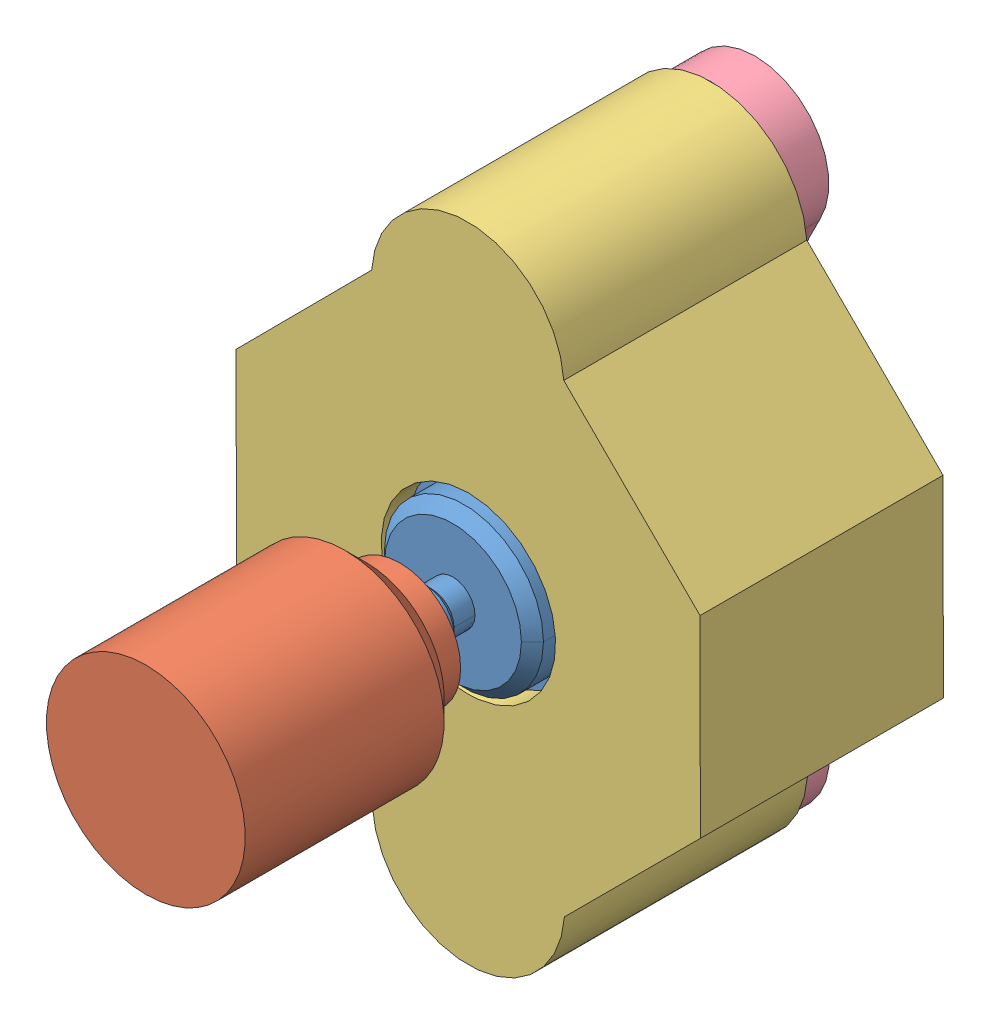
SolidWorks assembly funky switch assem, configuration Default. Lengths in mm.
Overall size (21.04 29.15 27.62).
4 component instances, 4 part files, 9 mates.
Components (placement in the parent):
- funkySwitch-1: funkySwitch [Default] at (11.7598 13.0171 12.1539) size (17.2 17.2 20.62)
- funky switch knob-1: funky switch knob [Default] at (11.7598 13.0171 26.5539) x (-1 0 0) z (0 1 0) size (9 11.5 9)
- funky switch mount-1: funky switch mount [Default] at (11.7598 13.0171 21.9539) x (-0.001455 0.999999 0) z (0 0 -1) size (29.12 21 11)
- funky switch mount lock-1: funky switch mount lock [Default] at (11.7421 13.0171 -2.0461) x (-0.00291 0.999996 0) z (0 0 1) size (29.12 6.72 3.2)
Mates (geometry in assembly coordinates):
- Concentric1: concentric aligned: cylinder of funkySwitch-1 through (11.7598 13.0171 9.0016) axis (0 0 -1) radius 1.25; cylinder of funky switch knob-1 through (11.7598 13.0171 29.5539) axis (0 0 -1) radius 1.45
- Parallel1: parallel anti-aligned: plane of funkySwitch-1 through (10.6373 13.5671 24.5539) normal (0 1 0); plane of funky switch knob-1 through (12.7598 14.0671 29.5539) normal (0 -1 0)
- Coincident2: coincident anti-aligned: plane of funkySwitch-1 through (11.7598 13.8671 29.5539) normal (0 0 1); plane of funky switch knob-1 through (11.7598 13.0171 29.5539) normal (0 0 -1)
- Concentric2: concentric aligned: cylinder of funkySwitch-1 through (11.7598 13.0171 22.6539) axis (0 0 -1) radius 3.6; cylinder of funky switch mount-1 through (11.7598 13.0171 21.9539) axis (0 0 -1) radius 3.95
- Coincident3: coincident anti-aligned: plane of funkySwitch-1 through (11.7598 13.0171 20.7539) normal (0 0 1); plane of funky switch mount-1 through (11.7302 23.218 20.7539) normal (0 0 -1)
- Parallel2: parallel anti-aligned: plane of funky switch mount-1 through (2.8598 16.7036 20.7539) normal (1 0 0); plane of funkySwitch-1 through (3.1598 13.5171 14.7039) normal (-1 0 0)
- Concentric7: concentric anti-aligned: cylinder of funky switch mount-1 through (11.7673 1.8 20.7539) axis (0 0 -1) radius 1.6; cylinder of funky switch mount lock-1 through (11.7673 1.8 8.9539) axis (0 0 1) radius 1.6
- Concentric8: concentric anti-aligned: cylinder of funky switch mount-1 through (11.7346 24.2343 20.7539) axis (0 0 -1) radius 1.6; cylinder of funky switch mount lock-1 through (11.7346 24.2343 8.9539) axis (0 0 1) radius 1.6
- Coincident4: coincident anti-aligned: plane of funky switch mount-1 through (11.7598 2.8163 10.9539) normal (0 0 -1); plane of funky switch mount lock-1 through (11.7673 1.8 10.9539) normal (0 0 1)
